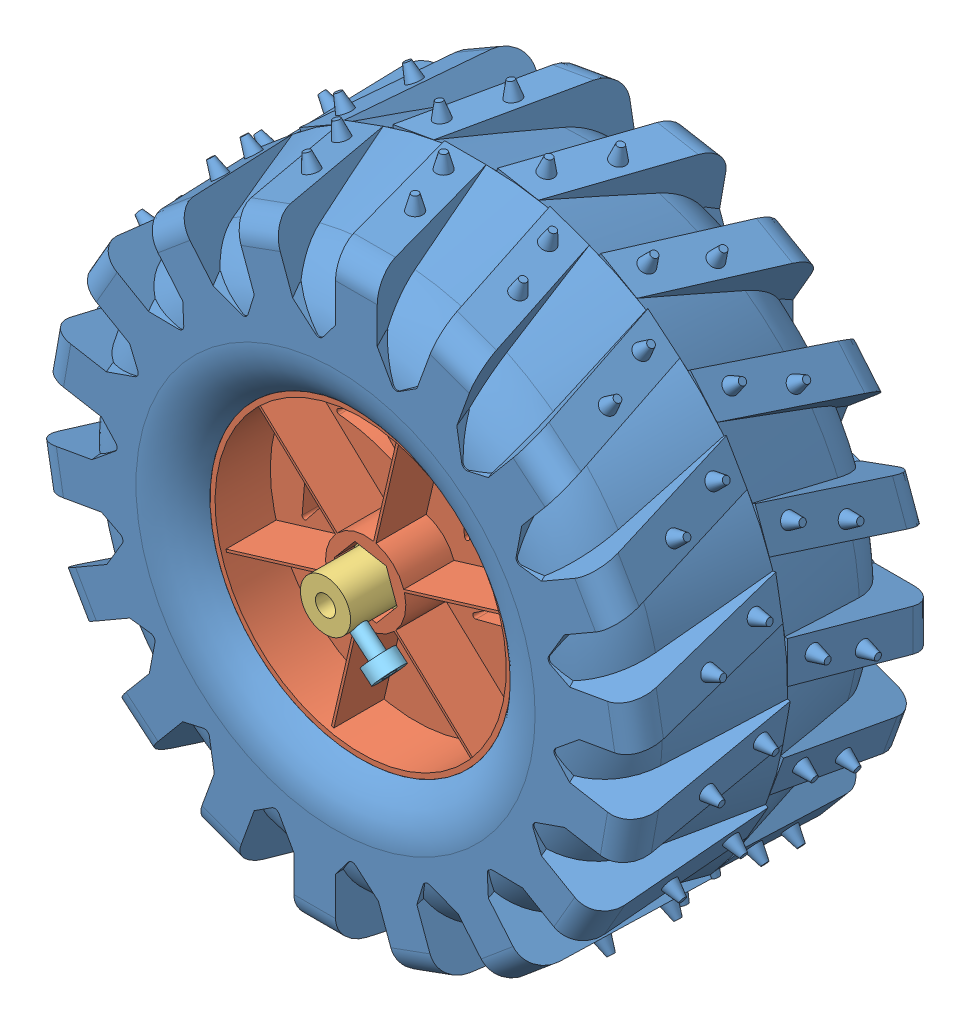
SolidWorks assembly right_wheel_asm, configuration Default. Lengths in mm.
Overall size (126 126 64.53).
5 component instances, 5 part files, 9 mates.
Components (placement in the parent):
- Tire-1: Tire [Varsayılan] at (37.7234 65.1994 132.8068) size (126 126 62.61)
- tire_rim-1: tire_rim [Varsayılan] at (14.8248 66.2056 132.8068) x (-0.909064 -0.416657 0) z (0 0 -1) size (60 60 50)
- wheel_adapter-1: wheel_adapter [Default] at (22.8801 68.188 123.8068) x (-0.646161 -0.763201 0) z (-0.763201 0.646161 0) size (12.7 16 11)
- m4_12mm_allen-1: m4_12mm_allen [Default] at (22.8801 68.188 125.8068) x (-0.635607 0.772013 0) z (-0.772013 -0.635607 0) size (8 16 8)
- m3_8mm_allen-1: m3_8mm_allen [Default] at (24.4065 66.8957 136.9766) x (-0.571035 -0.674467 0.467988) z (0.302396 0.357169 0.883735) size (6 11 6)
Mates (geometry in assembly coordinates):
- Concentric1: concentric: cylinder of Tire-1 through (22.8801 68.188 112.8068) axis (0 0 1) radius 30; cylinder of tire_rim-1 through (22.8801 68.188 82.8068) axis (0 0 1) radius 30
- Coincident2: coincident: plane of tire_rim-1 through (14.8248 66.2056 123.8068) normal (0 0 1); plane of wheel_adapter-1 through (22.8801 68.188 123.8068) normal (0 0 -1)
- Coincident3: coincident: plane of tire_rim-1 through (18.7764 63.3411 131.8068) normal (0.177991 0.984032 0); plane of wheel_adapter-1 through (18.7764 63.3411 125.8068) normal (-0.177991 -0.984032 0)
- Coincident4: coincident: plane of tire_rim-1 through (25.0258 62.2107 131.8068) normal (-0.763201 0.646161 0); plane of wheel_adapter-1 through (25.0258 62.2107 125.8068) normal (0.763201 -0.646161 0)
- Concentric2: concentric: cylinder of tire_rim-1 through (22.8801 68.188 132.8068) axis (0 0 -1) radius 2; cylinder of m4_12mm_allen-1 through (22.8801 68.188 113.8068) axis (0 0 1) radius 2
- Coincident5: coincident: plane of tire_rim-1 through (22.8801 68.188 113.8068) normal (0 0 -1); plane of m4_12mm_allen-1 through (22.8801 68.188 113.8068) normal (0 0 1)
- Concentric3: concentric: cylinder of wheel_adapter-1 through (32.0385 60.4341 134.9766) axis (-0.763201 0.646161 0) radius 1.5; cylinder of m3_8mm_allen-1 through (29.9953 62.164 134.9766) axis (-0.763201 0.646161 0) radius 1.5
- Tangent2: tangent: curve of wheel_adapter-1; circle of m3_8mm_allen-1
- Coincident6: coincident: circle of Tire-1; circle of tire_rim-1
